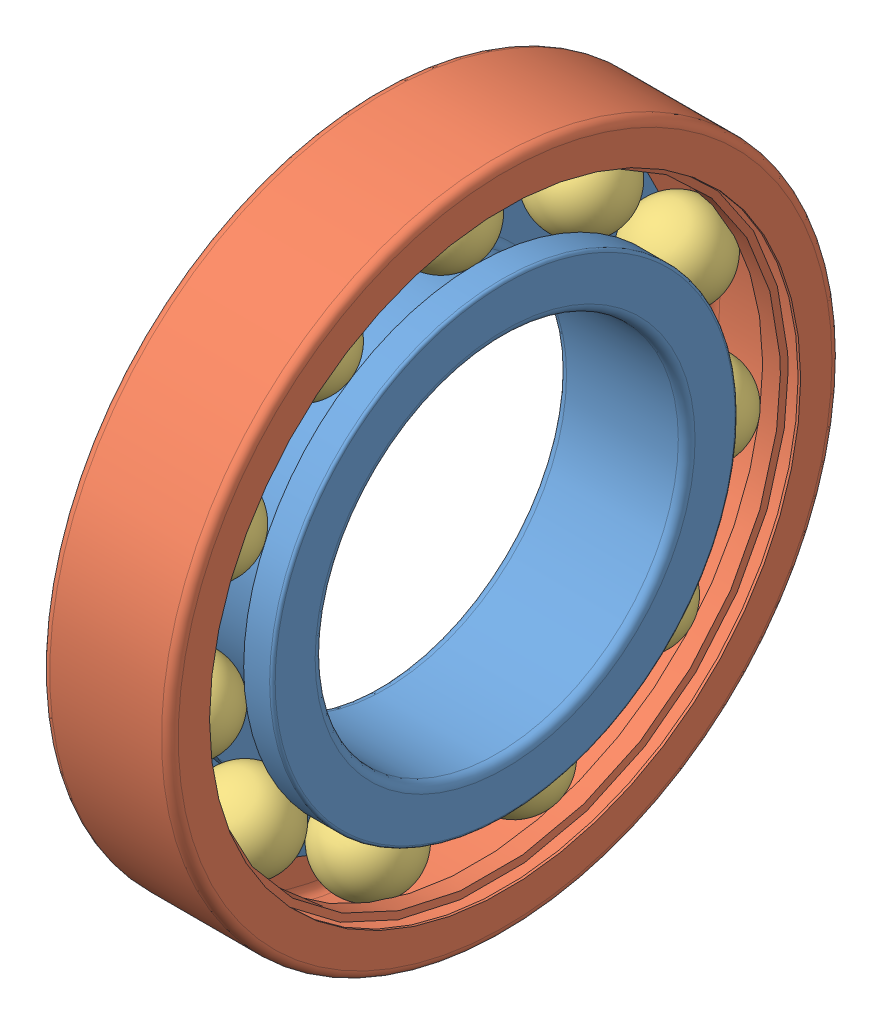
SolidWorks assembly Radiální ložisko , configuration Výchozí. Lengths in mm.
Overall size (233.7 319.2 319.2).
14 component instances, 3 part files, 0 mates.
Components (placement in the parent):
- DEFAULT-1: DEFAULT [Výchozí] at (14.4375 -20.3336 42.89) size (233.7 319.2 319.2)
  - DEFAULT-1: DEFAULT [Výchozí] at origin size (160.21 237.15 237.15)
  - DEFAULT-1-1: DEFAULT-1 [Výchozí] at origin size (233.7 319.2 319.2)
  - DEFAULT-2-1: DEFAULT-2 [Výchozí] at origin size (15.88 15.88 15.88)
  - DEFAULT-2-2: DEFAULT-2 [Výchozí] x (1 0 0) z (0 0.540641 0.841254) size (15.88 15.88 15.88)
  - DEFAULT-2-3: DEFAULT-2 [Výchozí] x (1 0 0) z (0 0.909632 0.415415) size (15.88 15.88 15.88)
  - DEFAULT-2-4: DEFAULT-2 [Výchozí] x (1 0 0) z (0 0.989821 -0.142315) size (15.88 15.88 15.88)
  - DEFAULT-2-5: DEFAULT-2 [Výchozí] x (1 0 0) z (0 0.75575 -0.654861) size (15.88 15.88 15.88)
  - DEFAULT-2-6: DEFAULT-2 [Výchozí] x (1 0 0) z (0 0.281733 -0.959493) size (15.88 15.88 15.88)
  - DEFAULT-2-7: DEFAULT-2 [Výchozí] x (1 0 0) z (0 -0.281733 -0.959493) size (15.88 15.88 15.88)
  - DEFAULT-2-8: DEFAULT-2 [Výchozí] x (1 0 0) z (0 -0.75575 -0.654861) size (15.88 15.88 15.88)
  - DEFAULT-2-9: DEFAULT-2 [Výchozí] x (1 0 0) z (0 -0.989821 -0.142315) size (15.88 15.88 15.88)
  - DEFAULT-2-10: DEFAULT-2 [Výchozí] x (1 0 0) z (0 -0.909632 0.415415) size (15.88 15.88 15.88)
  - DEFAULT-2-11: DEFAULT-2 [Výchozí] x (1 0 0) z (0 -0.540641 0.841254) size (15.88 15.88 15.88)
